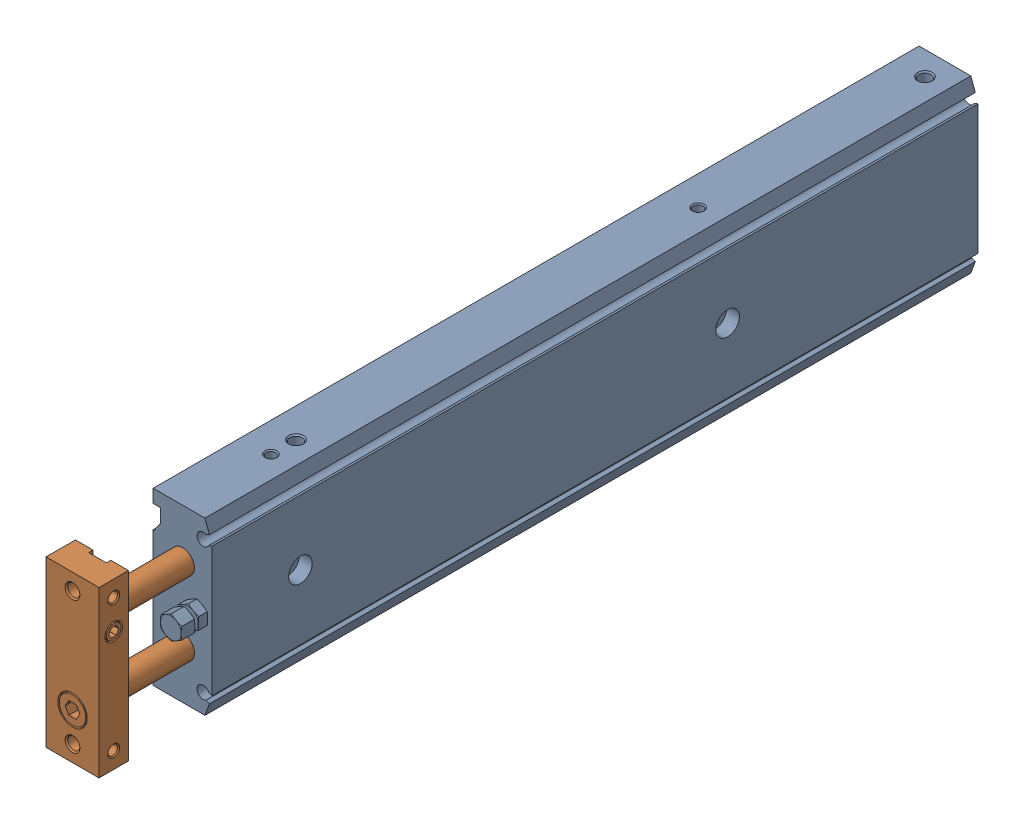
SolidWorks assembly air_cylinder_asembly, configuration По умолчанию. Lengths in mm.
Overall size (20.09 58.01 297.48).
2 component instances, 2 part files, 4 mates.
Components (placement in the parent):
- CXS2M16-200(0)_BODY-1: CXS2M16-200(0)_BODY [Default] at (20.2973 0.7731 89.7857) size (20.09 58.01 269.01)
- CXS2M16-200(0)_ROD-1: CXS2M16-200(0)_ROD [Default] at (20.2973 0.7731 108.1637) size (18.07 56 254.11)
Mates (geometry in assembly coordinates):
- Концентричный1: concentric aligned: cylinder of CXS2M16-200(0)_BODY-1 through (20.2973 -11.7269 -145.2143) axis (0 0 -1) radius 4; cylinder of CXS2M16-200(0)_ROD-1 through (20.2973 -11.7269 -126.8363) axis (0 0 -1) radius 4
- Граничное расстояние1: limit distance = 18.378 mm anti-aligned: plane of CXS2M16-200(0)_ROD-1 through (20.2973 21.2731 -126.8363) normal (0 0 -1); plane of CXS2M16-200(0)_BODY-1 through (20.2973 21.2731 -145.2143) normal (0 0 1)
- Граничное расстояние2: limit distance = 181.622 mm anti-aligned: plane of CXS2M16-200(0)_ROD-1 through (20.2973 17.2731 -121.8363) normal (0 0 1); plane of CXS2M16-200(0)_BODY-1 through (20.2973 17.2731 59.7857) normal (0 0 -1)
- Концентричный2: concentric aligned: cylinder of CXS2M16-200(0)_BODY-1 through (20.2973 13.2731 -145.2143) axis (0 0 -1) radius 4; cylinder of CXS2M16-200(0)_ROD-1 through (20.2973 13.2731 -126.8363) axis (0 0 -1) radius 4
